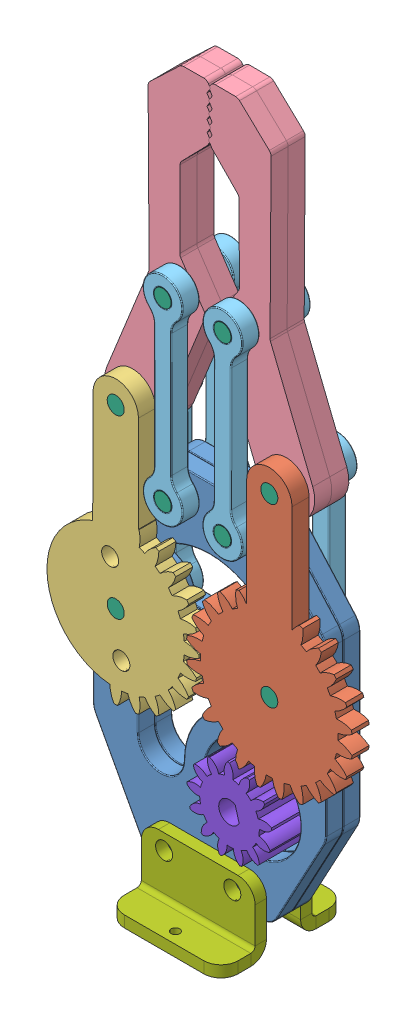
SolidWorks assembly Gripper Assembly, configuration Default. Lengths in mm.
Overall size (60 131.06 22).
25 component instances, 8 part files, 49 mates.
Components (placement in the parent):
- Part3-3-1: Part3-3 [Default] at origin size (41 62 3.03)
- part4-4-1: part4-4 [Default] at (13.5 37.5997 3) x (0 0 1) z (0 -1 0) size (3 29.07 49.54)
- part5-5-1: part5-5 [Default] at (-13.5 37.5997 6) x (0 0 -1) z (0.130526 -0.991445 0) size (3 26.63 49.27)
- Part1-1-1: Part1-1 [Default] at (-13.5 68.5997 0) x (0.374356 0.927285 0) z (0 0 1) size (60.3 20.75 3)
- Part2-2-1: Part2-2 [Default] at (-5.2398 58 4.5) x (-0.000786 1 0) z (0 0 1) size (38 7 3)
- Part2-2-2: Part2-2 [Default] at (5.2398 58 4.5) x (0.000786 1 0) z (0 0 1) size (38 7 3)
- Part1-1-2: Part1-1 [Default] at (13.5 68.5997 3) x (-0.374356 0.927285 0) z (0 0 -1) size (60.3 20.75 3)
- Part3-3-2: Part3-3 [Default] at (0 0 -3) size (41 62 3.03)
- Part1-1-3: Part1-1 [Default] at (13.5 68.5997 0) x (-0.374356 0.927285 0) z (0 0 -1) size (60.3 20.75 3)
- Part1-1-4: Part1-1 [Default] at (-13.5 68.5997 -3) x (0.374356 0.927285 0) z (0 0 1) size (60.3 20.75 3)
- Part2-2-5: Part2-2 [Default] at (-5.2398 58 -4.5) x (-0.000786 1 0) z (0 0 1) size (38 7 3)
- Part2-2-6: Part2-2 [Default] at (5.2398 58 -4.5) x (0.000786 1 0) z (0 0 1) size (38 7 3)
- Part2-2-9: Part2-2 [Default] at (13.5 37.5997 -4.5) x (0 1 0) z (0 0 1) size (38 7 3)
- Part2-2-10: Part2-2 [Default] at (-13.5 37.5997 -4.5) x (0 1 0) z (0 0 1) size (38 7 3)
- Part6-6-1: Part6-6 [Default] at (13.5 37.5997 6) x (-0.440468 0.897768 0) z (-0.897768 -0.440468 0) size (3 12 3)
- Part7-7-1: Part7-7 [Default] at (0 -5.279 3) x (0 -1 0) z (-1 0 0) size (12 8 20)
- Part6-6-2: Part6-6 [Default] at (-13.5 37.5997 -6) x (-0.359064 0.933313 0) z (0.933313 0.359064 0) size (3 12 3)
- Part6-6-3: Part6-6 [Default] at (-13.5 68.5997 -6) x (-0.923728 -0.383049 0) z (-0.383049 0.923728 0) size (3 12 3)
- Part6-6-4: Part6-6 [Default] at (-5.2398 58 -6) x (0.923728 0.383049 0) z (0.383049 -0.923728 0) size (3 12 3)
- Part6-6-5: Part6-6 [Default] at (-5.2642 89 -6) x (0.923728 0.383049 0) z (0.383049 -0.923728 0) size (3 12 3)
- Part6-6-6: Part6-6 [Default] at (5.2642 89 -6) x (0.923728 0.383049 0) z (0.383049 -0.923728 0) size (3 12 3)
- Part6-6-7: Part6-6 [Default] at (5.2398 58 -6) x (0.923728 0.383049 0) z (0.383049 -0.923728 0) size (3 12 3)
- Part6-6-8: Part6-6 [Default] at (13.5 68.5997 -6) x (0.923728 0.383049 0) z (0.383049 -0.923728 0) size (3 12 3)
- Part7-7-3: Part7-7 [Default] at (0 -5.279 -3) x (0 -1 0) z (1 0 0) size (12 8 20)
- part8-8-1: part8-8 [Default] at (7.5 17.5997 7) x (0 0 -1) z (0.964513 0.264035 0) size (13 17.5 17.5)
Mates (geometry in assembly coordinates):
- Concentric1: concentric aligned: cylinder of Part3-3-1 through (13.5 37.5997 3) axis (0 0 -1) radius 1.5; cylinder of part4-4-1 through (13.5 37.5997 53.0001) axis (0 0 -1) radius 1.5
- Coincident1: coincident anti-aligned: plane of Part3-3-1 through (0 0 3) normal (0 0 1); plane of part4-4-1 through (13.5 37.5997 3) normal (0 0 -1)
- Concentric2: concentric anti-aligned: cylinder of Part3-3-1 through (-13.5 37.5997 3) axis (0 0 -1) radius 1.5; cylinder of part5-5-1 through (-13.5 37.5997 -44.0001) axis (0 0 1) radius 1.5
- Coincident3: coincident anti-aligned: plane of Part3-3-1 through (0 0 3) normal (0 0 1); plane of part5-5-1 through (-13.5 37.5997 3) normal (0 0 -1)
- Concentric3: concentric aligned: cylinder of Part3-3-1 through (-5.2398 58 3) axis (0 0 -1) radius 1.5; cylinder of Part2-2-1 through (-5.2398 58 6) axis (0 0 -1) radius 1.5
- Coincident4: coincident anti-aligned: plane of Part3-3-1 through (0 0 3) normal (0 0 1); plane of Part2-2-1 through (-5.2398 58 3) normal (0 0 -1)
- Concentric4: concentric anti-aligned: cylinder of part5-5-1 through (-13.5 68.5997 3) axis (0 0 1) radius 1.5; cylinder of Part1-1-1 through (-13.5 68.5997 3) axis (0 0 -1) radius 1.5
- Concentric5: concentric aligned: cylinder of Part1-1-1 through (-5.2642 89 3) axis (0 0 -1) radius 1.5; cylinder of Part2-2-1 through (-5.2642 89 6) axis (0 0 -1) radius 1.5
- Concentric6: concentric anti-aligned: cylinder of part4-4-1 through (13.5 68.5997 6) axis (0 0 -1) radius 1.5; cylinder of Part1-1-2 through (13.5 68.5997 0) axis (0 0 1) radius 1.5
- Concentric7: concentric aligned: cylinder of Part3-3-1 through (5.2398 58 3) axis (0 0 -1) radius 1.5; cylinder of Part2-2-2 through (5.2398 58 6) axis (0 0 -1) radius 1.5
- Concentric8: concentric anti-aligned: cylinder of Part2-2-2 through (5.2642 89 6) axis (0 0 -1) radius 1.5; cylinder of Part1-1-2 through (5.2642 89 0) axis (0 0 1) radius 1.5
- Coincident8: coincident anti-aligned: plane of part4-4-1 through (13.5 37.5997 3) normal (0 0 -1); plane of Part1-1-2 through (13.5 68.5997 3) normal (0 0 1)
- Coincident9: coincident anti-aligned: plane of part5-5-1 through (-13.5 37.5997 3) normal (0 0 -1); plane of Part1-1-1 through (-13.5 68.5997 3) normal (0 0 1)
- Coincident10: coincident anti-aligned: plane of Part3-3-1 through (0 0 3) normal (0 0 1); plane of Part2-2-2 through (5.2398 58 3) normal (0 0 -1)
- Concentric11: concentric aligned: cylinder of Part3-3-2 through (13.5 37.5997 0) axis (0 0 -1) radius 1.5; cylinder of Part2-2-9 through (13.5 37.5997 -3) axis (0 0 -1) radius 1.5
- Concentric12: concentric anti-aligned: cylinder of Part1-1-3 through (13.5 68.5997 -3) axis (0 0 1) radius 1.5; cylinder of Part2-2-9 through (13.5 68.5997 -3) axis (0 0 -1) radius 1.5
- Coincident11: coincident anti-aligned: plane of Part3-3-2 through (0 0 -3) normal (0 0 -1); plane of Part2-2-9 through (13.5 37.5997 -3) normal (0 0 1)
- Concentric13: concentric aligned: cylinder of Part3-3-2 through (-13.5 37.5997 0) axis (0 0 -1) radius 1.5; cylinder of Part2-2-10 through (-13.5 37.5997 -3) axis (0 0 -1) radius 1.5
- Concentric14: concentric aligned: cylinder of Part1-1-4 through (-13.5 68.5997 0) axis (0 0 -1) radius 1.5; cylinder of Part2-2-10 through (-13.5 68.5997 -3) axis (0 0 -1) radius 1.5
- Coincident12: coincident anti-aligned: plane of Part3-3-2 through (0 0 -3) normal (0 0 -1); plane of Part2-2-10 through (-13.5 37.5997 -3) normal (0 0 1)
- Concentric15: concentric anti-aligned: cylinder of part4-4-1 through (13.5 37.5997 53.0001) axis (0 0 -1) radius 1.5; cylinder of Part6-6-1 through (13.5 37.5997 6) axis (0 0 1) radius 1.5
- Coincident15: coincident aligned: plane of Part2-2-9 through (13.5 37.5997 -6) normal (0 0 -1); plane of Part6-6-8 through (12.1144 68.0251 -6) normal (0 0 -1)
- Coincident16: coincident anti-aligned: plane of Part3-3-1 through (0 0 3) normal (0 0 1); plane of Part7-7-1 through (-10 -5.279 3) normal (0 0 -1)
- Concentric16: concentric anti-aligned: cylinder of Part3-3-1 through (-6 4 3) axis (0 0 -1) radius 1.5; cylinder of Part7-7-1 through (-6 4 3) axis (0 0 1) radius 1.5
- Concentric17: concentric anti-aligned: cylinder of Part3-3-1 through (6 4 3) axis (0 0 -1) radius 1.5; cylinder of Part7-7-1 through (6 4 3) axis (0 0 1) radius 1.5
- Concentric18: concentric anti-aligned: cylinder of part5-5-1 through (-13.5 37.5997 -44.0001) axis (0 0 1) radius 1.5; cylinder of Part6-6-2 through (-13.5 37.5997 -6) axis (0 0 -1) radius 1.5
- Coincident17: coincident aligned: plane of part5-5-1 through (-13.5 37.5997 6) normal (0 0 1); plane of Part6-6-3 through (-12.1144 69.1743 6) normal (0 0 1)
- Concentric19: concentric anti-aligned: cylinder of part5-5-1 through (-13.5 68.5997 3) axis (0 0 1) radius 1.5; cylinder of Part6-6-3 through (-13.5 68.5997 -6) axis (0 0 -1) radius 1.5
- Coincident18: coincident aligned: plane of part5-5-1 through (-13.5 37.5997 6) normal (0 0 1); plane of Part6-6-3 through (-12.1144 69.1743 6) normal (0 0 1)
- Concentric20: concentric aligned: cylinder of Part2-2-1 through (-5.2398 58 6) axis (0 0 -1) radius 1.5; cylinder of Part6-6-4 through (-5.2398 58 -6) axis (0 0 -1) radius 1.5
- Coincident19: coincident aligned: plane of Part2-2-1 through (-5.2398 58 6) normal (0 0 1); plane of Part6-6-4 through (-6.6254 57.4254 6) normal (0 0 1)
- Concentric21: concentric aligned: cylinder of Part2-2-1 through (-5.2642 89 6) axis (0 0 -1) radius 1.5; cylinder of Part6-6-5 through (-5.2642 89 -6) axis (0 0 -1) radius 1.5
- Coincident20: coincident aligned: plane of Part2-2-1 through (-5.2398 58 6) normal (0 0 1); plane of Part6-6-5 through (-6.6498 88.4254 6) normal (0 0 1)
- Concentric22: concentric aligned: cylinder of Part2-2-2 through (5.2642 89 6) axis (0 0 -1) radius 1.5; cylinder of Part6-6-6 through (5.2642 89 -6) axis (0 0 -1) radius 1.5
- Coincident21: coincident aligned: plane of Part2-2-2 through (5.2398 58 6) normal (0 0 1); plane of Part6-6-6 through (3.8786 88.4254 6) normal (0 0 1)
- Concentric23: concentric aligned: cylinder of Part2-2-2 through (5.2398 58 6) axis (0 0 -1) radius 1.5; cylinder of Part6-6-7 through (5.2398 58 -6) axis (0 0 -1) radius 1.5
- Coincident22: coincident aligned: plane of Part2-2-2 through (5.2398 58 6) normal (0 0 1); plane of Part6-6-7 through (3.8542 57.4254 6) normal (0 0 1)
- Concentric24: concentric aligned: cylinder of part4-4-1 through (13.5 68.5997 6) axis (0 0 -1) radius 1.5; cylinder of Part6-6-8 through (13.5 68.5997 -6) axis (0 0 -1) radius 1.5
- Coincident23: coincident aligned: plane of part4-4-1 through (13.5 37.5997 6) normal (0 0 1); plane of Part6-6-8 through (12.1144 68.0251 6) normal (0 0 1)
- Coincident25: coincident anti-aligned: plane of Part3-3-2 through (0 0 -3) normal (0 0 -1); plane of Part7-7-3 through (10 -5.279 -3) normal (0 0 1)
- Concentric27: concentric aligned: cylinder of Part3-3-2 through (6 4 0) axis (0 0 -1) radius 1.5; cylinder of Part7-7-3 through (6 4 -3) axis (0 0 -1) radius 1.5
- Concentric28: concentric aligned: cylinder of Part3-3-2 through (-6 4 0) axis (0 0 -1) radius 1.5; cylinder of Part7-7-3 through (-6 4 -3) axis (0 0 -1) radius 1.5
- Concentric29: concentric anti-aligned: cylinder of Part3-3-1 through (7.5 17.5997 3) axis (0 0 -1) radius 8.5; cylinder of part8-8-1 through (7.5 17.5997 -6) axis (0 0 1) radius 8.75
- Coincident26: coincident anti-aligned: plane of Part3-3-2 through (0 0 -3) normal (0 0 -1); plane of part8-8-1 through (7.5 17.5997 -3) normal (0 0 1)
- LimitAngle1: limit planar angle = 3.141593 rad anti-aligned: plane of part5-5-1 through (-17.5 37.5997 3) normal (-1 0 0); plane of Part3-3-1 through (-20.5 47.8997 3) normal (-1 0 0)
- GearMate1: gear = 1 : 1 mm: cylinder of part5-5-1 through (-13.5 37.5997 3) axis (0 0 1) radius 12.0927; cylinder of part4-4-1 through (13.5 37.5997 6) axis (0 0 -1) radius 12.0927
- GearMate2: gear = 13 : 24 mm: cylinder of part8-8-1 through (7.5 17.5997 -3) axis (0 0 1) radius 5.249; cylinder of part4-4-1 through (13.5 37.5997 6) axis (0 0 -1) radius 12.0927
- Coincident27: coincident aligned: plane of Part2-2-10 through (-13.5 37.5997 -6) normal (0 0 -1); plane of Part6-6-2 through (-12.9614 36.1997 -6) normal (0 0 -1)
- Coincident28: coincident aligned: plane of Part2-2-9 through (13.5 37.5997 -6) normal (0 0 -1); plane of Part6-6-1 through (14.1607 36.2531 -6) normal (0 0 -1)
